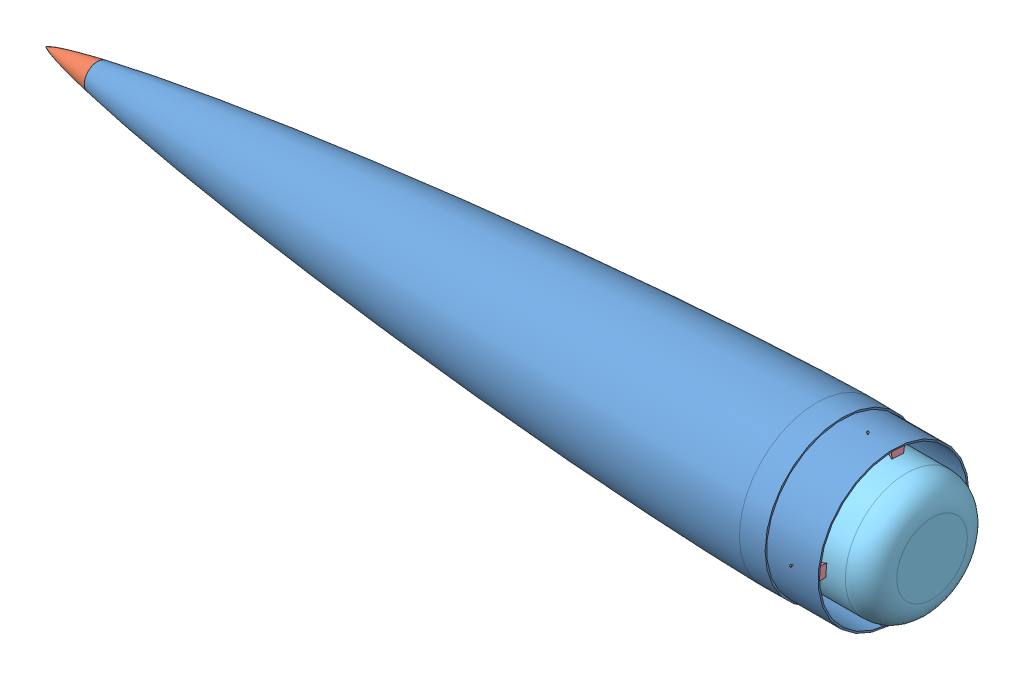
SolidWorks assembly 10003-R03_NOSE_CONE_ASSEMBLY, configuration Default. Lengths in mm.
Overall size (1752.6 337.52 337.52).
8 component instances, 5 part files, 5 mates.
Components (placement in the parent):
- 14015-R03_NOSE_CONE_MAIN_PORTION-1: 14015-R03_NOSE_CONE_MAIN_PORTION [Default] at (-306.7187 919.2546 1145.5242) size (1574.8 304.98 304.98)
- 14016-R02_NOSE_CONE_METAL_TIP-1: 14016-R02_NOSE_CONE_METAL_TIP [Default] at (-306.7187 919.2546 1145.5242) x (1 0 0) z (0 0.723211 0.690628) size (114.3 51.57 51.57)
- 14022-R01_NYLON_SHEAR_PINS-1: 14022-R01_NYLON_SHEAR_PINS [Default] at (1318.8813 919.2546 993.1242) x (0 0 1) z (-0.242152 -0.970238 0) size (8.19 4.11 4.11)
- 14022-R01_NYLON_SHEAR_PINS-2: 14022-R01_NYLON_SHEAR_PINS [Default] at (1318.8813 766.8546 1145.5242) x (0 1 0) z (-0.982149 0 0.188105) size (8.19 4.11 4.11)
- 14022-R01_NYLON_SHEAR_PINS-3: 14022-R01_NYLON_SHEAR_PINS [Default] at (1318.8813 919.2546 1297.9242) x (0 0 -1) z (0.923728 0.383049 0) size (8.19 4.11 4.11)
- 14022-R01_NYLON_SHEAR_PINS-4: 14022-R01_NYLON_SHEAR_PINS [Default] at (1318.8813 1071.6546 1145.5242) x (0 -1 0) z (-0.546944 0 0.837169) size (8.19 4.11 4.11)
- 14017-R02_NOSE_CONE_TABS-1: 14017-R02_NOSE_CONE_TABS [Default] at (1369.6813 915.5518 1291.5273) x (1 0 0) z (0 -0.999679 -0.025353) size (12.7 292.1 292.1)
- 14044-R01_Parachute_Stand-In-1: 14044-R01_Parachute_Stand-In [Default] at (683.8813 919.2546 1145.5242) x (0 0.595063 -0.803679) z (1 0 0) size (241.3 241.3 762)
Mates (geometry in assembly coordinates):
- Coincident1: coincident: circle of 14015-R03_NOSE_CONE_MAIN_PORTION-1; circle of 14016-R02_NOSE_CONE_METAL_TIP-1
- Concentric9: concentric: circle of 14015-R03_NOSE_CONE_MAIN_PORTION-1; circle of 14017-R02_NOSE_CONE_TABS-1
- Coincident2: coincident: plane of 14015-R03_NOSE_CONE_MAIN_PORTION-1 through (1369.6813 919.2546 1145.5242) normal (1 0 0); plane of 14017-R02_NOSE_CONE_TABS-1 through (1369.6813 787.3856 1165.3433) normal (1 0 0)
- Concentric10: concentric: circle of 14015-R03_NOSE_CONE_MAIN_PORTION-1; circle of 14044-R01_Parachute_Stand-In-1
- Distance3: distance = 76.2 mm: plane of 14015-R03_NOSE_CONE_MAIN_PORTION-1 through (1369.6813 919.2546 1145.5242) normal (1 0 0); plane of 14044-R01_Parachute_Stand-In-1 through (1445.8813 919.2546 1145.5242) normal (1 0 0)
